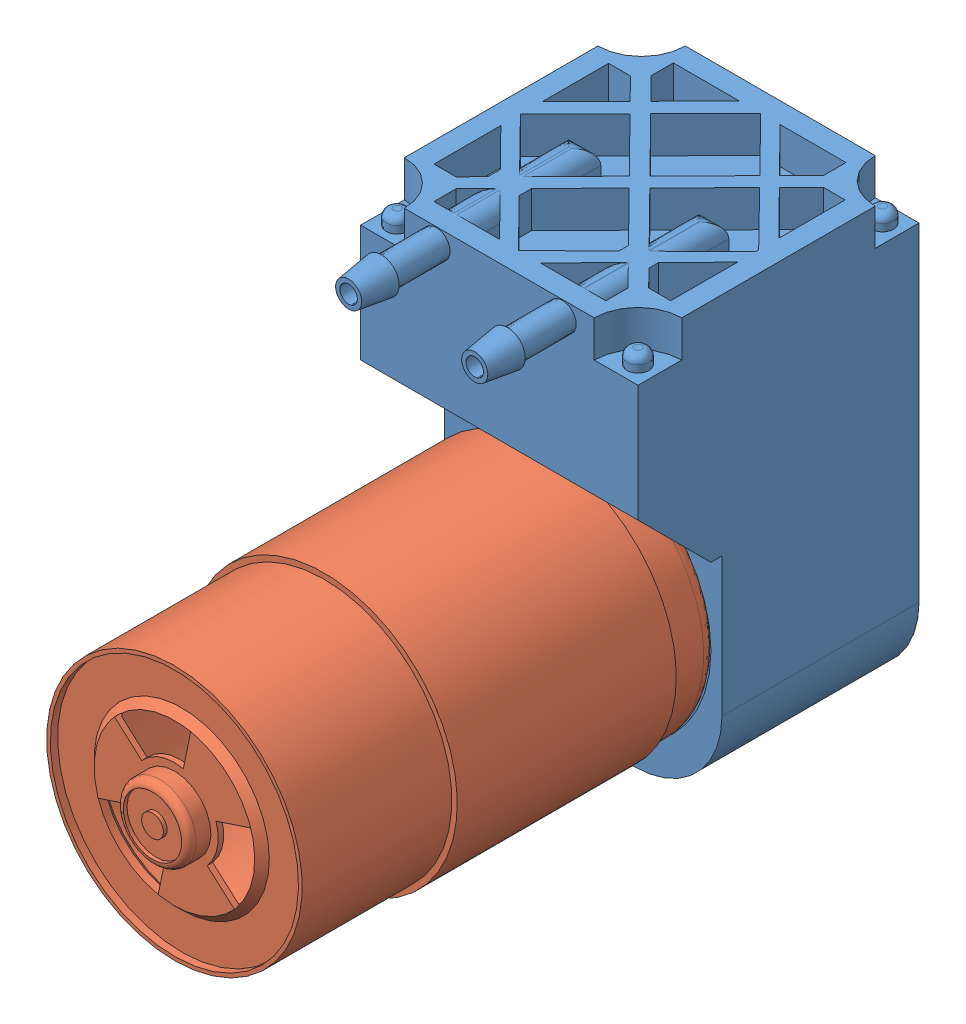
SolidWorks assembly vacuum pump assembly, configuration Default. Lengths in mm.
Overall size (45.44 66.15 86).
2 component instances, 2 part files, 0 mates.
Components (placement in the parent):
- vacuum section-1: vacuum section [Default] at (48.2505 35.8771 7.1194) size (38 62.43 50.5)
- motor shell-1: motor shell [Default] at (48.2505 23.8771 33.1194) x (-0.28691 -0.957957 0) z (0 0 1) size (36.5 36.5 63)
